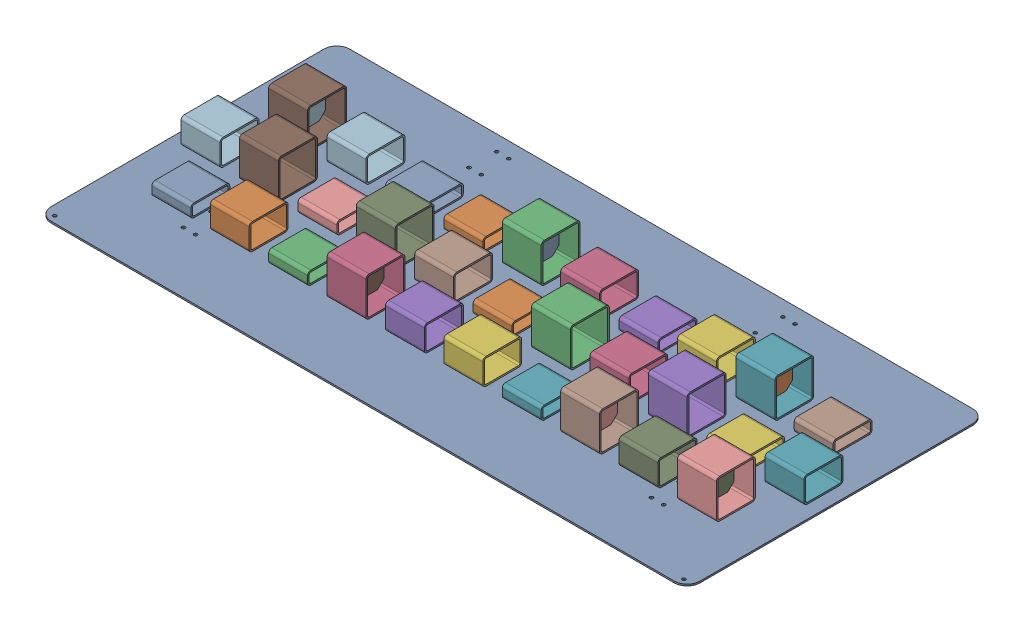
SolidWorks assembly GE-16060_ASM, configuration Default. Lengths in mm.
Overall size (1270 79.38 584.2).
38 component instances, 5 part files, 0 mates.
Components (placement in the parent):
- GE-16016-1: GE-16016 [Default] at origin size (1270 3.17 584.2)
- GE-16060-01-1: GE-16060-01 [Default] at (-38.1 3.175 0) x (1 0 0) z (0 -1 0) size (76.2 76.2 25.4)
- GE-16060-03-1: GE-16060-03 [Default] at (76.2 3.175 0) size (76.2 76.2 76.2)
- GE-16060-02-1: GE-16060-02 [Default] at (190.5 3.175 0) size (76.2 50.8 76.2)
- GE-16060-03-2: GE-16060-03 [Default] at (304.8 3.175 0) size (76.2 76.2 76.2)
- GE-16060-01-2: GE-16060-01 [Default] at (419.1 3.175 0) x (1 0 0) z (0 -1 0) size (76.2 76.2 25.4)
- GE-16060-02-2: GE-16060-02 [Default] at (533.4 3.175 0) size (76.2 50.8 76.2)
- GE-16060-02-3: GE-16060-02 [Default] at (-152.4 3.175 0) size (76.2 50.8 76.2)
- GE-16060-03-3: GE-16060-03 [Default] at (-266.7 3.175 0) size (76.2 76.2 76.2)
- GE-16060-01-3: GE-16060-01 [Default] at (-381 3.175 0) x (1 0 0) z (0 -1 0) size (76.2 76.2 25.4)
- GE-16060-03-4: GE-16060-03 [Default] at (-495.3 3.175 0) size (76.2 76.2 76.2)
- GE-16060-02-4: GE-16060-02 [Default] at (-609.6 3.175 0) size (76.2 50.8 76.2)
- GE-16060-01-4: GE-16060-01 [Default] at (-552.45 3.175 114.3) x (1 0 0) z (0 -1 0) size (76.2 76.2 25.4)
- GE-16060-02-5: GE-16060-02 [Default] at (-438.15 3.175 114.3) size (76.2 50.8 76.2)
- GE-16060-01-5: GE-16060-01 [Default] at (-323.85 3.175 114.3) x (1 0 0) z (0 -1 0) size (76.2 76.2 25.4)
- GE-16060-03-5: GE-16060-03 [Default] at (-209.55 3.175 114.3) size (76.2 76.2 76.2)
- GE-16060-02-6: GE-16060-02 [Default] at (-95.25 3.175 114.3) size (76.2 50.8 76.2)
- GE-16060-02-7: GE-16060-02 [Default] at (19.05 3.175 114.3) size (76.2 50.8 76.2)
- GE-16060-01-6: GE-16060-01 [Default] at (133.35 3.175 114.3) x (1 0 0) z (0 -1 0) size (76.2 76.2 25.4)
- GE-16060-03-6: GE-16060-03 [Default] at (247.65 3.175 114.3) size (76.2 76.2 76.2)
- GE-16060-02-8: GE-16060-02 [Default] at (361.95 3.175 114.3) size (76.2 50.8 76.2)
- GE-16060-03-7: GE-16060-03 [Default] at (476.25 3.175 114.3) size (76.2 76.2 76.2)
- GE-16060-03-8: GE-16060-03 [Default] at (-552.45 3.175 -114.3) size (76.2 76.2 76.2)
- GE-16060-02-9: GE-16060-02 [Default] at (-438.15 3.175 -114.3) size (76.2 50.8 76.2)
- GE-16060-01-7: GE-16060-01 [Default] at (-323.85 3.175 -114.3) x (1 0 0) z (0 -1 0) size (76.2 76.2 25.4)
- GE-16060-01-8: GE-16060-01 [Default] at (-209.55 3.175 -114.3) x (1 0 0) z (0 -1 0) size (76.2 76.2 25.4)
- GE-16060-03-9: GE-16060-03 [Default] at (-95.25 3.175 -114.3) size (76.2 76.2 76.2)
- GE-16060-02-10: GE-16060-02 [Default] at (19.05 3.175 -114.3) size (76.2 50.8 76.2)
- GE-16060-01-9: GE-16060-01 [Default] at (133.35 3.175 -114.3) x (1 0 0) z (0 -1 0) size (76.2 76.2 25.4)
- GE-16060-02-11: GE-16060-02 [Default] at (247.65 3.175 -114.3) size (76.2 50.8 76.2)
- GE-16060-03-10: GE-16060-03 [Default] at (361.95 3.175 -114.3) size (76.2 76.2 76.2)
- GE-16060-01-10: GE-16060-01 [Default] at (476.25 3.175 -114.3) x (1 0 0) z (0 -1 0) size (76.2 76.2 25.4)
- GE-16060-04-1: GE-16060-04 [Default] at (511.175 6.35 149.225) size (3.17 69.85 69.85)
- GE-16060-04-2: GE-16060-04 [Default] at (282.575 6.35 149.225) size (3.17 69.85 69.85)
- GE-16060-04-3: GE-16060-04 [Default] at (-174.625 6.35 149.225) size (3.17 69.85 69.85)
- GE-16060-04-4: GE-16060-04 [Default] at (-517.525 6.35 -79.375) size (3.17 69.85 69.85)
- GE-16060-04-5: GE-16060-04 [Default] at (-60.325 6.35 -79.375) size (3.17 69.85 69.85)
- GE-16060-04-6: GE-16060-04 [Default] at (396.875 6.35 -79.375) size (3.17 69.85 69.85)
